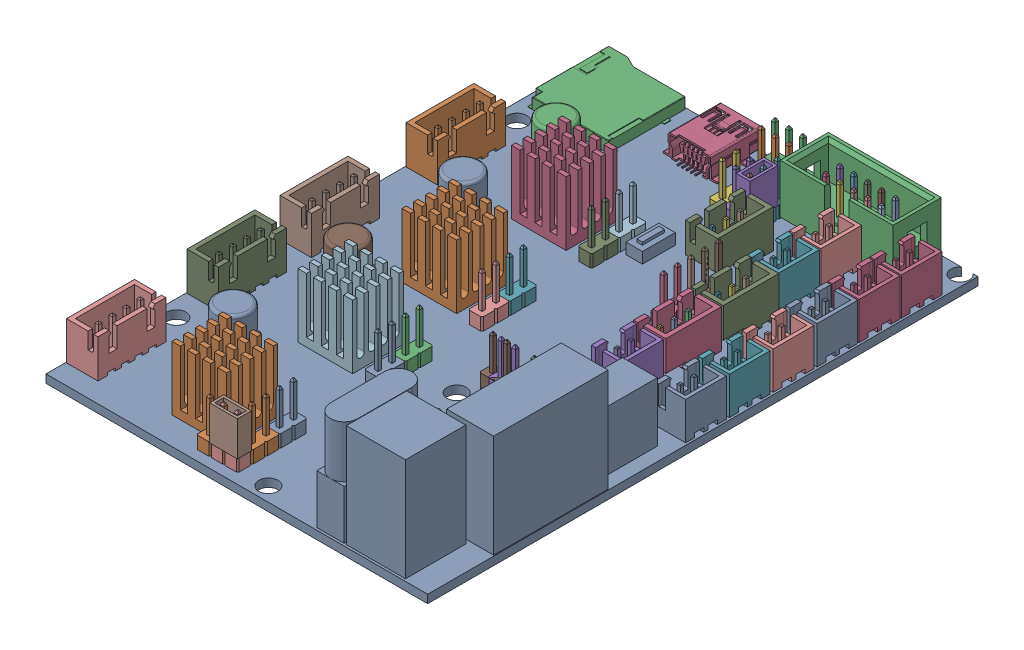
SolidWorks assembly BTT SKR MINI E3 V1.2 v2, configuration Default. Lengths in mm.
Overall size (69.7 22.28 101.21).
116 component instances, 62 part files, 0 mates.
Components (placement in the parent):
- SKR Mini E3 1.2-1: SKR Mini E3 1.2 [Default] at (0.4313 -1.6126 -0.8701) size (69.7 20.32 100.5)
- 4 pin Header-1: 4 pin Header [Default] at (-25.3481 -5.4688 -25.9996) x (0 0 1) z (-1 0 0) size (12.4 10.4 5.75)
- JST 2pin-1: JST 2pin [Default] at (9.9082 -0.1126 -7.1947) x (-1 0 0) z (0 0 -1) size (5.73 10.3 7.43)
  - JST 2pin_2-1: JST 2pin_2 [Default] at origin size (0.63 1.95 0.64)
  - JST 2pin_3-1: JST 2pin_3 [Default] at origin size (0.63 1.95 0.63)
  - JST 2pin-1: JST 2pin [Default] at origin size (5.73 6.85 7.43)
- Header 3 pin-1: Header 3 pin [Default] at (1.8482 -0.1126 -33.0477) x (0 0 1) z (-1 0 0) size (10.16 7.2 5.9)
  - Header 3 pin-1: Header 3 pin [Default] at origin size (0.6 4.4 0.6)
  - Header 3 pin_2-1: Header 3 pin_2 [Default] at origin size (0.6 4.4 0.6)
  - Header 3 pin_6-1: Header 3 pin_6 [Default] at origin size (0.6 4.4 0.6)
  - Header 3 pin_4-1: Header 3 pin_4 [Default] at origin size (10.16 7 5.9)
  - Header 3 pin_5-1: Header 3 pin_5 [Default] at origin size (0.6 0.7 1.65)
  - Header 3 pin_3-1: Header 3 pin_3 [Default] at origin size (0.6 0.7 1.9)
  - Header 3 pin_7-1: Header 3 pin_7 [Default] at origin size (0.6 0.2 0.5)
- 100uF 35V 6.3x7-1: 100uF 35V 6.3x7 [Default] at (-28.7944 0.8874 26.9674) x (-1 0 0) z (0 0 -1) size (6.62 7.75 7.2)
- TMC 2209 Heatsink-1: TMC 2209 Heatsink [Default] at (-21.6787 1.8374 38.0799) x (1 0 0) z (0 1 0) size (9.98 9.3 11.65)
- sdreader-1: sdreader [Default] at (-33.9687 -1.5126 -38.3866) x (0 0 1) z (0 1 0) size (15 16 2)
- 2 Pin connector-1: 2 Pin connector [Default] at (-0.9803 -0.3666 -42.1218) x (0 0 1) z (-1 0 0) size (5.08 11.94 2.54)
- Jumper-1: Jumper [Default] at (-15.4835 0 -3.6239) size (2.55 6.35 5.06)
- Header 3 pin (1)-1: Header 3 pin (1) [Default] at (12.9215 -0.1126 -22.9838) x (0 0 1) z (-1 0 0) size (10.16 7.2 5.9)
  - Header 3 pin (1)_3-1: Header 3 pin (1)_3 [Default] at origin size (0.6 4.4 0.6)
  - Header 3 pin (1)_5-1: Header 3 pin (1)_5 [Default] at origin size (0.6 4.4 0.6)
  - Header 3 pin (1)_6-1: Header 3 pin (1)_6 [Default] at origin size (0.6 4.4 0.6)
  - Header 3 pin (1)_2-1: Header 3 pin (1)_2 [Default] at origin size (10.16 7 5.9)
  - Header 3 pin (1)_7-1: Header 3 pin (1)_7 [Default] at origin size (0.6 0.7 1.65)
  - Header 3 pin (1)-1: Header 3 pin (1) [Default] at origin size (0.6 0.7 1.9)
  - Header 3 pin (1)_4-1: Header 3 pin (1)_4 [Default] at origin size (0.6 0.2 0.5)
- Header 3 pin (2)-1: Header 3 pin (2) [Default] at (12.9215 -0.1126 -12.4838) x (0 0 1) z (-1 0 0) size (10.16 7.2 5.9)
  - Header 3 pin (2)_5-1: Header 3 pin (2)_5 [Default] at origin size (0.6 4.4 0.6)
  - Header 3 pin (2)_4-1: Header 3 pin (2)_4 [Default] at origin size (0.6 4.4 0.6)
  - Header 3 pin (2)_2-1: Header 3 pin (2)_2 [Default] at origin size (0.6 4.4 0.6)
  - Header 3 pin (2)_6-1: Header 3 pin (2)_6 [Default] at origin size (10.16 7 5.9)
  - Header 3 pin (2)_7-1: Header 3 pin (2)_7 [Default] at origin size (0.6 0.7 1.65)
  - Header 3 pin (2)_3-1: Header 3 pin (2)_3 [Default] at origin size (0.6 0.7 1.9)
  - Header 3 pin (2)-1: Header 3 pin (2) [Default] at origin size (0.6 0.2 0.5)
- 4 pin Header-2: 4 pin Header [Default] at (-25.3481 -5.4688 -2.9996) x (0 0 1) z (-1 0 0) size (12.4 10.4 5.75)
- 4 pin Header-3: 4 pin Header [Default] at (-25.3481 -5.4688 14.0004) x (0 0 1) z (-1 0 0) size (12.4 10.4 5.75)
- 4 pin Header-4: 4 pin Header [Default] at (-25.3481 -5.4688 36.0004) x (0 0 1) z (-1 0 0) size (12.4 10.4 5.75)
- 100uF 35V 6.3x7-2: 100uF 35V 6.3x7 [Default] at (-28.7944 0.8874 5.9674) x (-1 0 0) z (0 0 -1) size (6.62 7.75 7.2)
- TMC 2209 Heatsink-2: TMC 2209 Heatsink [Default] at (-21.6787 1.8374 15.0799) x (1 0 0) z (0 1 0) size (9.98 9.3 11.65)
- 100uF 35V 6.3x7-3: 100uF 35V 6.3x7 [Default] at (-28.7944 0.8874 -15.0326) x (-1 0 0) z (0 0 -1) size (6.62 7.75 7.2)
- TMC 2209 Heatsink-3: TMC 2209 Heatsink [Default] at (-21.6787 1.8374 -3.9201) x (1 0 0) z (0 1 0) size (9.98 9.3 11.65)
- 100uF 35V 6.3x7-4: 100uF 35V 6.3x7 [Default] at (-28.7944 0.8874 -32.0326) x (-1 0 0) z (0 0 -1) size (6.62 7.75 7.2)
- TMC 2209 Heatsink-4: TMC 2209 Heatsink [Default] at (-21.6787 1.8374 -23.9201) x (1 0 0) z (0 1 0) size (9.98 9.3 11.65)
- JST 2pin-2: JST 2pin [Default] at (9.9082 -0.1126 -35.6947) x (-1 0 0) z (0 0 -1) size (5.73 10.3 7.43)
  - JST 2pin_2-1: JST 2pin_2 [Default] at origin size (0.63 1.95 0.64)
  - JST 2pin_3-1: JST 2pin_3 [Default] at origin size (0.63 1.95 0.63)
  - JST 2pin-1: JST 2pin [Default] at origin size (5.73 6.85 7.43)
- JST 2pin-3: JST 2pin [Default] at (9.9082 -0.1126 -43.3829) x (-1 0 0) z (0 0 -1) size (5.73 10.3 7.43)
  - JST 2pin_2-1: JST 2pin_2 [Default] at origin size (0.63 1.95 0.64)
  - JST 2pin_3-1: JST 2pin_3 [Default] at origin size (0.63 1.95 0.63)
  - JST 2pin-1: JST 2pin [Default] at origin size (5.73 6.85 7.43)
- JST 2pin-4: JST 2pin [Default] at (21.4082 -0.1126 -7.1947) x (-1 0 0) z (0 0 -1) size (5.73 10.3 7.43)
  - JST 2pin_2-1: JST 2pin_2 [Default] at origin size (0.63 1.95 0.64)
  - JST 2pin_3-1: JST 2pin_3 [Default] at origin size (0.63 1.95 0.63)
  - JST 2pin-1: JST 2pin [Default] at origin size (5.73 6.85 7.43)
- JST 2pin-5: JST 2pin [Default] at (21.4082 -0.1126 -38.8829) x (-1 0 0) z (0 0 -1) size (5.73 10.3 7.43)
  - JST 2pin_2-1: JST 2pin_2 [Default] at origin size (0.63 1.95 0.64)
  - JST 2pin_3-1: JST 2pin_3 [Default] at origin size (0.63 1.95 0.63)
  - JST 2pin-1: JST 2pin [Default] at origin size (5.73 6.85 7.43)
- JST 2pin-6: JST 2pin [Default] at (21.4082 -0.1126 -15.1947) x (-1 0 0) z (0 0 -1) size (5.73 10.3 7.43)
  - JST 2pin_2-1: JST 2pin_2 [Default] at origin size (0.63 1.95 0.64)
  - JST 2pin_3-1: JST 2pin_3 [Default] at origin size (0.63 1.95 0.63)
  - JST 2pin-1: JST 2pin [Default] at origin size (5.73 6.85 7.43)
- JST 2pin-7: JST 2pin [Default] at (21.4082 -0.1126 -23.1947) x (-1 0 0) z (0 0 -1) size (5.73 10.3 7.43)
  - JST 2pin_2-1: JST 2pin_2 [Default] at origin size (0.63 1.95 0.64)
  - JST 2pin_3-1: JST 2pin_3 [Default] at origin size (0.63 1.95 0.63)
  - JST 2pin-1: JST 2pin [Default] at origin size (5.73 6.85 7.43)
- JST 2pin-8: JST 2pin [Default] at (21.4082 -0.1126 -31.1947) x (-1 0 0) z (0 0 -1) size (5.73 10.3 7.43)
  - JST 2pin_2-1: JST 2pin_2 [Default] at origin size (0.63 1.95 0.64)
  - JST 2pin_3-1: JST 2pin_3 [Default] at origin size (0.63 1.95 0.63)
  - JST 2pin-1: JST 2pin [Default] at origin size (5.73 6.85 7.43)
- JST 2pin-9: JST 2pin [Default] at (21.4082 -0.1126 -46.5829) x (-1 0 0) z (0 0 -1) size (5.73 10.3 7.43)
  - JST 2pin_2-1: JST 2pin_2 [Default] at origin size (0.63 1.95 0.64)
  - JST 2pin_3-1: JST 2pin_3 [Default] at origin size (0.63 1.95 0.63)
  - JST 2pin-1: JST 2pin [Default] at origin size (5.73 6.85 7.43)
- 2 Pin connector-2: 2 Pin connector [Default] at (-3.4803 -0.3666 -42.1218) x (0 0 1) z (-1 0 0) size (5.08 11.94 2.54)
- 2 Pin connector-3: 2 Pin connector [Default] at (-5.9803 -0.3666 -42.1218) x (0 0 1) z (-1 0 0) size (5.08 11.94 2.54)
- 2 Pin connector-4: 2 Pin connector [Default] at (-0.9803 -0.3666 -44.6618) x (0 0 1) z (-1 0 0) size (5.08 11.94 2.54)
- Jumper-2: Jumper [Default] at (-48.7447 0 30.2029) x (0 0 1) z (-1 0 0) size (2.55 6.35 5.06)
- 2 Pin connector (5)-1: 2 Pin connector (5) [Default] at (11.0313 -0.1126 9.1899) x (-1 0 0) z (0 0 -1) size (5.08 11.94 2.54)
- 2 Pin connector (11)-1: 2 Pin connector (11) [Default] at (-10.2712 -0.3666 44.6158) x (-1 0 0) z (0 0 -1) size (5.08 11.94 2.54)
- 2 Pin connector (12)-1: 2 Pin connector (12) [Default] at (6.8963 -0.1126 -23.5114) x (0 0 -1) z (1 0 0) size (5.08 11.94 2.54)
- 2 Pin connector (13)-1: 2 Pin connector (13) [Default] at (10.6557 -0.1126 28.8793) x (0 0 -1) z (1 0 0) size (5.08 11.94 2.54)
  - Component1369-1: Component1369 [Default] at origin size (5.08 11.94 2.54)
- 2 Pin connector (14)-1: 2 Pin connector (14) [Default] at (-10.2606 -0.3666 16.4669) x (0 0 1) z (-1 0 0) size (5.08 11.94 2.54)
- 2 Pin connector (15)-1: 2 Pin connector (15) [Default] at (-10.2606 -0.3666 39.4669) x (0 0 1) z (-1 0 0) size (5.08 11.94 2.54)
- 2 Pin connector (16)-1: 2 Pin connector (16) [Default] at (-10.2606 -0.3666 11.4669) x (0 0 1) z (-1 0 0) size (5.08 11.94 2.54)
- 2 Pin connector (17)-1: 2 Pin connector (17) [Default] at (6.8963 -0.1126 -16.0114) x (0 0 -1) z (1 0 0) size (5.08 11.94 2.54)
- 2 Pin connector (18)-1: 2 Pin connector (18) [Default] at (5.0143 -0.1126 9.2211) x (-1 0 0) z (0 0 -1) size (5.08 11.94 2.54)
- 2 Pin connector (19)-1: 2 Pin connector (19) [Default] at (8.1557 -0.1126 28.8793) x (0 0 -1) z (1 0 0) size (5.08 11.94 2.54)
  - Component1370-1: Component1370 [Default] at origin size (5.08 11.94 2.54)
- 2 Pin connector (20)-1: 2 Pin connector (20) [Default] at (-10.2606 -0.3666 -7.5331) x (0 0 1) z (-1 0 0) size (5.08 11.94 2.54)
- 2 Pin connector (21)-1: 2 Pin connector (21) [Default] at (6.8963 -0.1126 -21.0114) x (0 0 -1) z (1 0 0) size (5.08 11.94 2.54)
- 2 Pin connector (22)-1: 2 Pin connector (22) [Default] at (-10.2606 -0.3666 -22.5331) x (0 0 1) z (-1 0 0) size (5.08 11.94 2.54)
- 2 Pin connector (23)-1: 2 Pin connector (23) [Default] at (-10.2606 -0.3666 -2.5331) x (0 0 1) z (-1 0 0) size (5.08 11.94 2.54)
- 2 Pin connector (24)-1: 2 Pin connector (24) [Default] at (3.4513 -0.1126 9.1899) x (-1 0 0) z (0 0 -1) size (5.08 11.94 2.54)
- 2 Pin connector (25)-1: 2 Pin connector (25) [Default] at (-10.2606 -0.3666 -27.5331) x (0 0 1) z (-1 0 0) size (5.08 11.94 2.54)
- 2 Pin connector (26)-1: 2 Pin connector (26) [Default] at (-10.2606 -0.3666 34.4669) x (0 0 1) z (-1 0 0) size (5.08 11.94 2.54)
- 2 Pin connector (27)-1: 2 Pin connector (27) [Default] at (-12.7712 -0.3666 44.6158) x (-1 0 0) z (0 0 -1) size (5.08 11.94 2.54)
- DS1013-10SSiB v1-1: DS1013-10SSiB v1 [Default] at (5.7052 0 -46.8226) x (1 0 0) z (0 1 0) size (20.6 9.22 12.4)
  - body-1: body [Default] at origin size (20.6 9.22 12.4)
    - body_3-1: body_3 [Default] at origin size (20.6 9.22 9.3)
    - body_2-1: body_2 [Default] at origin size (0.64 0.64 11.5)
    - body_7-1: body_7 [Default] at origin size (0.64 0.64 11.5)
    - body_8-1: body_8 [Default] at origin size (0.64 0.64 11.5)
    - body_4-1: body_4 [Default] at origin size (0.64 0.64 11.5)
    - body-1: body [Default] at origin size (0.64 0.64 11.5)
    - body_9-1: body_9 [Default] at origin size (0.64 0.64 11.5)
    - body_6-1: body_6 [Default] at origin size (0.64 0.64 11.5)
    - body_10-1: body_10 [Default] at origin size (0.64 0.64 11.5)
    - body_5-1: body_5 [Default] at origin size (0.64 0.64 11.5)
    - body_11-1: body_11 [Default] at origin size (0.64 0.64 11.5)
- zl201-3_p2-54_l7-62_w2-54_h8-89 v1-1: zl201-3_p2-54_l7-62_w2-54_h8-89 v1 [Default] at (-7.1165 -0.1 -47.85) size (7.62 11.94 2.54)
- zl201-3_p2-54_l7-62_w2-54_h8-89 v1-2: zl201-3_p2-54_l7-62_w2-54_h8-89 v1 [Default] at (-7.1165 -0.1 -50.35) size (7.62 11.94 2.54)
- USB_MINI_B_SMD v35 v1-1: USB_MINI_B_SMD v35 v1 [Default] at (-15.7973 -0.1 -52.75) x (-1 0 0) z (0 0 -1) size (9.9 4.23 9.9)
